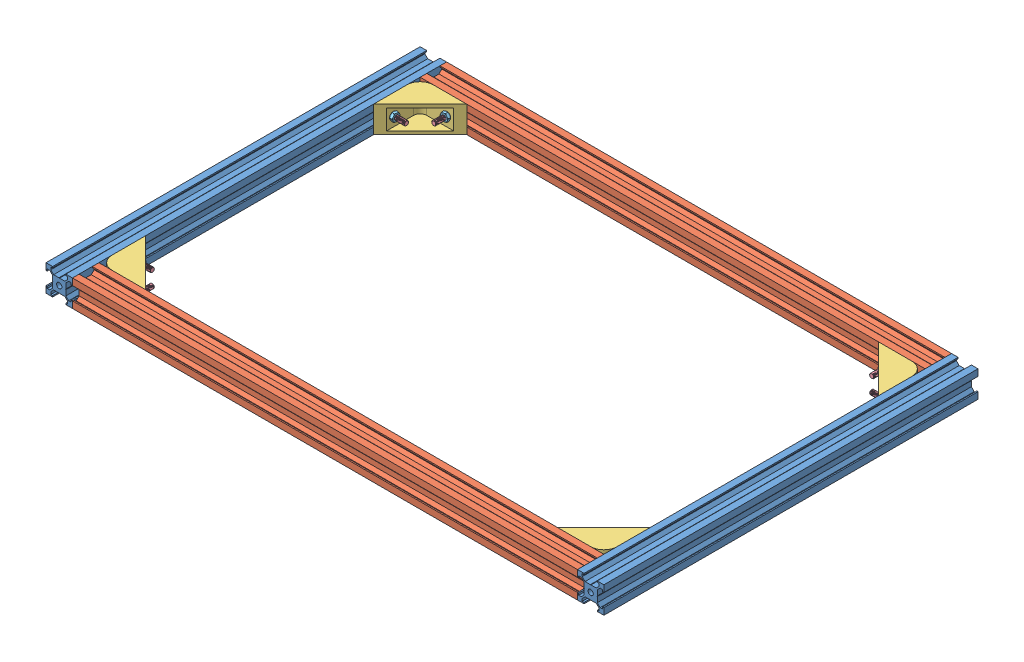
SolidWorks assembly Bottom Frame, configuration Default. Lengths in mm.
Overall size (422 20 283).
28 component instances, 5 part files, 29 mates.
Components (placement in the parent):
- T-slot aluminium profiles(283)-2: T-slot aluminium profiles(283) [Default] at (139.2356 156.3375 52.1184) size (20 20 283)
- T-slot aluminium profiles(382)-2: T-slot aluminium profiles(382) [Default] at (531.2356 156.3375 325.1184) x (0 0 1) z (-1 0 0) size (20 20 382)
- T-slot aluminium profiles(382)-3: T-slot aluminium profiles(382) [Default] at (531.2356 156.3375 62.1184) x (0 0 1) z (-1 0 0) size (20 20 382)
- T-slot aluminium profiles(283)-3: T-slot aluminium profiles(283) [Default] at (541.2356 156.3375 52.1184) size (20 20 283)
- Connector and Nut-1: Connector and Nut [Default] at (495.0014 140.4658 271.3786) size (38.1 20 38.1) (flexible)
  - connector-1: connector [Default] at (36.2342 15.8717 43.7398) size (35.36 20 35.36)
  - T-bolt-1: T-bolt [Default] at (38.0779 15.8717 18.3844) x (-1 0 0) z (0 0 -1) size (17.8 12.7 9.5)
  - hexagon nut style 1_is-2: hexagon nut style 1_is [IS 1364-3 - M3-W-N] at (28.8342 15.8717 18.3844) x (0 0.996107 0.088148) z (-1 0 0) size (5.5 6.35 2.4)
  - T-bolt-2: T-bolt [Default] at (10.8788 15.8717 45.5835) x (0 0 -1) z (1 0 0) size (17.8 12.7 9.5)
  - hexagon nut style 1_is-3: hexagon nut style 1_is [IS 1364-3 - M3-W-N] at (10.8788 15.8717 36.3398) x (0.175203 0.984532 0) z (0 0 -1) size (5.5 6.35 2.4)
- Connector and Nut-2: Connector and Nut [Default] at (487.4958 140.4658 108.3525) x (0 0 -1) z (1 0 0) size (38.1 20 38.1) (flexible)
  - connector-1: connector [Default] at (36.2342 15.8717 43.7398) size (35.36 20 35.36)
  - T-bolt-1: T-bolt [Default] at (38.0779 15.8717 18.3844) x (-1 0 0) z (0 0 -1) size (17.8 12.7 9.5)
  - hexagon nut style 1_is-2: hexagon nut style 1_is [IS 1364-3 - M3-W-N] at (28.8342 15.8717 18.3844) x (0 0.996107 0.088148) z (-1 0 0) size (5.5 6.35 2.4)
  - T-bolt-2: T-bolt [Default] at (10.8788 15.8717 45.5835) x (0 0 -1) z (1 0 0) size (17.8 12.7 9.5)
  - hexagon nut style 1_is-3: hexagon nut style 1_is [IS 1364-3 - M3-W-N] at (10.8788 15.8717 36.3398) x (0.175203 0.984532 0) z (0 0 -1) size (5.5 6.35 2.4)
- Connector and Nut-3: Connector and Nut [Default] at (192.9754 140.4658 278.8842) x (0 0 1) z (-1 0 0) size (38.1 20 38.1) (flexible)
  - connector-1: connector [Default] at (36.2342 15.8717 43.7398) size (35.36 20 35.36)
  - T-bolt-1: T-bolt [Default] at (38.0779 15.8717 18.3844) x (-1 0 0) z (0 0 -1) size (17.8 12.7 9.5)
  - hexagon nut style 1_is-2: hexagon nut style 1_is [IS 1364-3 - M3-W-N] at (28.8342 15.8717 18.3844) x (0 0.996107 0.088148) z (-1 0 0) size (5.5 6.35 2.4)
  - T-bolt-2: T-bolt [Default] at (10.8788 15.8717 45.5835) x (0 0 -1) z (1 0 0) size (17.8 12.7 9.5)
  - hexagon nut style 1_is-3: hexagon nut style 1_is [IS 1364-3 - M3-W-N] at (10.8788 15.8717 36.3398) x (0.175203 0.984532 0) z (0 0 -1) size (5.5 6.35 2.4)
- Connector and Nut-4: Connector and Nut [Default] at (185.4698 140.4658 115.8582) x (-1 0 0) z (0 0 -1) size (38.1 20 38.1) (flexible)
  - connector-1: connector [Default] at (36.2342 15.8717 43.7398) size (35.36 20 35.36)
  - T-bolt-1: T-bolt [Default] at (38.0779 15.8717 18.3844) x (-1 0 0) z (0 0 -1) size (17.8 12.7 9.5)
  - hexagon nut style 1_is-2: hexagon nut style 1_is [IS 1364-3 - M3-W-N] at (28.8342 15.8717 18.3844) x (0 0.996107 0.088148) z (-1 0 0) size (5.5 6.35 2.4)
  - T-bolt-2: T-bolt [Default] at (10.8788 15.8717 45.5835) x (0 0 -1) z (1 0 0) size (17.8 12.7 9.5)
  - hexagon nut style 1_is-3: hexagon nut style 1_is [IS 1364-3 - M3-W-N] at (10.8788 15.8717 36.3398) x (0.175203 0.984532 0) z (0 0 -1) size (5.5 6.35 2.4)
Mates (geometry in assembly coordinates):
- Coincident1: coincident: plane of T-slot aluminium profiles(283)-2 through (149.2356 156.3375 335.1184) normal (1 0 0); plane of T-slot aluminium profiles(382)-2 through (149.2356 156.3375 325.1184) normal (-1 0 0)
- Coincident2: coincident: plane of T-slot aluminium profiles(283)-2 through (139.2356 166.3375 335.1184) normal (0 1 0); plane of T-slot aluminium profiles(382)-2 through (149.2356 166.3375 325.1184) normal (0 1 0)
- Coincident3: coincident: plane of T-slot aluminium profiles(283)-2 through (139.2356 156.3375 335.1184) normal (0 0 1); plane of T-slot aluminium profiles(382)-2 through (149.2356 156.3375 335.1184) normal (0 0 1)
- Coincident4: coincident: plane of T-slot aluminium profiles(283)-2 through (149.2356 156.3375 335.1184) normal (1 0 0); plane of T-slot aluminium profiles(382)-3 through (149.2356 156.3375 62.1184) normal (-1 0 0)
- Coincident5: coincident: plane of T-slot aluminium profiles(283)-2 through (139.2356 166.3375 335.1184) normal (0 1 0); plane of T-slot aluminium profiles(382)-3 through (149.2356 166.3375 62.1184) normal (0 1 0)
- Coincident6: coincident: plane of T-slot aluminium profiles(283)-2 through (139.2356 156.3375 52.1184) normal (0 0 -1); plane of T-slot aluminium profiles(382)-3 through (149.2356 156.3375 52.1184) normal (0 0 -1)
- Coincident7: coincident: plane of T-slot aluminium profiles(382)-3 through (531.2356 156.3375 62.1184) normal (1 0 0); plane of T-slot aluminium profiles(283)-3 through (531.2356 156.3375 335.1184) normal (-1 0 0)
- Coincident8: coincident: plane of T-slot aluminium profiles(382)-3 through (149.2356 156.3375 52.1184) normal (0 0 -1); plane of T-slot aluminium profiles(283)-3 through (541.2356 156.3375 52.1184) normal (0 0 -1)
- Coincident9: coincident: plane of T-slot aluminium profiles(382)-3 through (149.2356 166.3375 62.1184) normal (0 1 0); plane of T-slot aluminium profiles(283)-3 through (541.2356 166.3375 335.1184) normal (0 1 0)
- Coincident10: coincident: plane of T-slot aluminium profiles(382)-2 through (149.2356 156.3375 316.0621) normal (0 0 1); plane of Connector and Nut-1/T-bolt-2 through (510.6302 149.9875 316.0621) normal (0 0 -1)
- Coincident11: coincident: plane of T-slot aluminium profiles(382)-2 through (149.2356 166.3375 325.1184) normal (0 1 0); plane of Connector and Nut-1/connector-1 through (531.2356 166.3375 315.1184) normal (0 1 0)
- Coincident12: coincident: plane of T-slot aluminium profiles(283)-3 through (532.1793 156.3375 335.1184) normal (1 0 0); plane of Connector and Nut-1/T-bolt-1 through (532.1793 149.9875 285.013) normal (-1 0 0)
- Coincident13: coincident: plane of T-slot aluminium profiles(283)-3 through (531.2356 156.3375 335.1184) normal (-1 0 0); plane of Connector and Nut-1/connector-1 through (531.2356 166.3375 315.1184) normal (1 0 0)
- Coincident14: coincident: plane of T-slot aluminium profiles(382)-2 through (149.2356 156.3375 315.1184) normal (0 0 -1); plane of Connector and Nut-1/connector-1 through (495.8802 166.3375 315.1184) normal (0 0 1)
- Coincident15: coincident: plane of T-slot aluminium profiles(283)-3 through (541.2356 166.3375 335.1184) normal (0 1 0); plane of Connector and Nut-2/connector-1 through (531.2356 166.3375 72.1184) normal (0 1 0)
- Coincident16: coincident: plane of T-slot aluminium profiles(382)-3 through (149.2356 156.3375 71.1746) normal (0 0 -1); plane of Connector and Nut-2/T-bolt-1 through (501.1302 149.9875 71.1746) normal (0 0 1)
- Coincident17: coincident: plane of T-slot aluminium profiles(283)-3 through (532.1793 156.3375 335.1184) normal (1 0 0); plane of Connector and Nut-2/T-bolt-2 through (532.1793 149.9875 92.7237) normal (-1 0 0)
- Coincident18: coincident: plane of T-slot aluminium profiles(382)-3 through (149.2356 156.3375 72.1184) normal (0 0 1); plane of Connector and Nut-2/connector-1 through (531.2356 166.3375 72.1184) normal (0 0 -1)
- Coincident19: coincident: plane of T-slot aluminium profiles(283)-3 through (531.2356 156.3375 335.1184) normal (-1 0 0); plane of Connector and Nut-2/connector-1 through (531.2356 166.3375 107.4737) normal (1 0 0)
- Coincident20: coincident: plane of T-slot aluminium profiles(382)-2 through (149.2356 166.3375 325.1184) normal (0 1 0); plane of Connector and Nut-3/connector-1 through (149.2356 166.3375 315.1184) normal (0 1 0)
- Coincident21: coincident: plane of T-slot aluminium profiles(382)-2 through (149.2356 156.3375 316.0621) normal (0 0 1); plane of Connector and Nut-3/T-bolt-1 through (179.3409 149.9875 316.0621) normal (0 0 -1)
- Coincident22: coincident: plane of T-slot aluminium profiles(283)-2 through (148.2918 156.3375 335.1184) normal (-1 0 0); plane of Connector and Nut-3/T-bolt-2 through (148.2918 149.9875 294.513) normal (1 0 0)
- Coincident23: coincident: plane of T-slot aluminium profiles(382)-2 through (149.2356 156.3375 315.1184) normal (0 0 -1); plane of Connector and Nut-3/connector-1 through (149.2356 166.3375 315.1184) normal (0 0 1)
- Coincident24: coincident: plane of T-slot aluminium profiles(283)-2 through (149.2356 156.3375 335.1184) normal (1 0 0); plane of Connector and Nut-3/connector-1 through (149.2356 166.3375 279.763) normal (-1 0 0)
- Coincident25: coincident: plane of T-slot aluminium profiles(283)-2 through (139.2356 166.3375 335.1184) normal (0 1 0); plane of Connector and Nut-4/connector-1 through (149.2356 166.3375 72.1184) normal (0 1 0)
- Coincident26: coincident: plane of T-slot aluminium profiles(382)-3 through (149.2356 156.3375 72.1184) normal (0 0 1); plane of Connector and Nut-4/connector-1 through (184.5909 166.3375 72.1184) normal (0 0 -1)
- Coincident27: coincident: plane of T-slot aluminium profiles(382)-3 through (149.2356 156.3375 71.1746) normal (0 0 -1); plane of Connector and Nut-4/T-bolt-2 through (169.8409 149.9875 71.1746) normal (0 0 1)
- Coincident28: coincident: plane of T-slot aluminium profiles(283)-2 through (148.2918 156.3375 335.1184) normal (-1 0 0); plane of Connector and Nut-4/T-bolt-1 through (148.2918 149.9875 102.2237) normal (1 0 0)
- Coincident29: coincident: plane of T-slot aluminium profiles(283)-2 through (149.2356 156.3375 335.1184) normal (1 0 0); plane of Connector and Nut-4/connector-1 through (149.2356 166.3375 72.1184) normal (-1 0 0)
